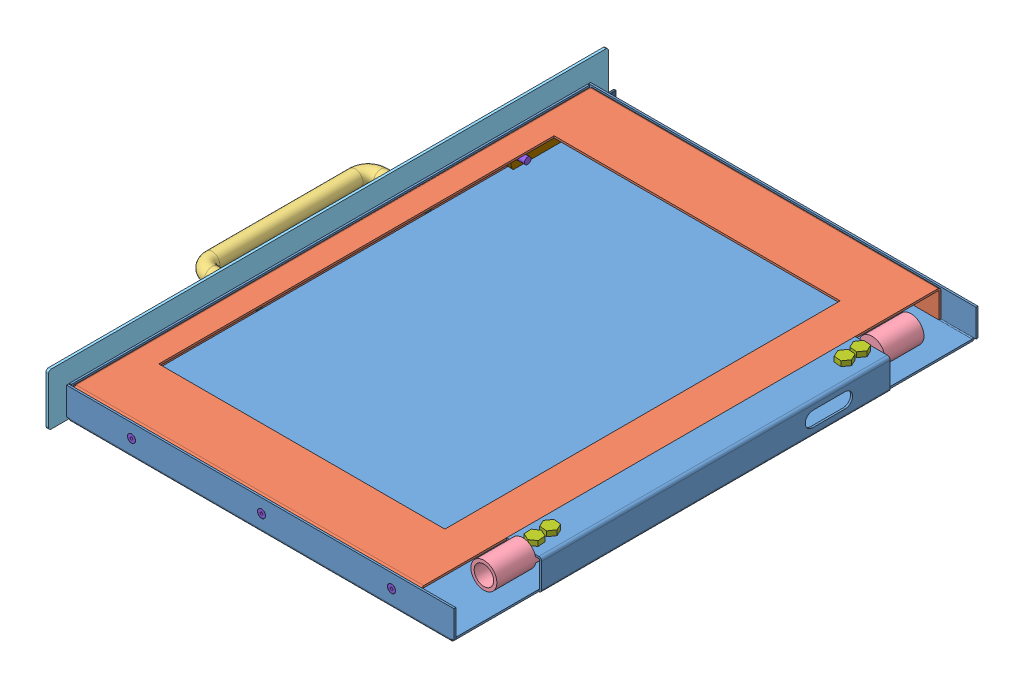
SolidWorks assembly MONITOR, configuration Valor predeterminado. Lengths in mm.
Overall size (341 40 430.56).
23 component instances, 10 part files, 51 mates.
Components (placement in the parent):
- 500040100-1: 500040100 [Valor predeterminado] at origin size (298 23.5 403.09)
- 500100100-1: 500100100 [Valor predeterminado] at (1.5 20.5 -401.59) x (1 0 0) z (0 0 -1) size (269.5 21.26 400.09)
- 500110100-1: 500110100 [Valor predeterminado] at (-2 12 -269.045) x (0 0 1) z (1 0 0) size (142 12 41)
- 500070100-1: 500070100 [Default<Como usinado>] at (283.75 18.5 -67.3) x (1 0 0) z (0 0 -1) size (20 20 60)
- 500070100-2: 500070100 [Default<Como usinado>] at (283.75 18.5 -335.79) size (20 20 60)
- 500120100-1: 500120100 [Valor predeterminado] at (-2 18.5 -201.545) x (0 0 -1) z (-1 0 0) size (430.56 40 2)
- PARAFUSO ALLEN CILÍNDRICO DIN 912-1: PARAFUSO ALLEN CILÍNDRICO DIN 912 [M6x20] at (9 12 -269.045) x (0 0.596353 -0.802722) z (-1 0 0) size (10 10 26)
- PARAFUSO ALLEN CILÍNDRICO DIN 912-2: PARAFUSO ALLEN CILÍNDRICO DIN 912 [M6x20] at (9 12 -139.045) x (0 0.596353 -0.802722) z (-1 0 0) size (10 10 26)
- PARAFUSO SEXTAVADO DIN 933-1: PARAFUSO SEXTAVADO DIN 933 [M6 x 10] at (283.75 24.2 -88.3) x (-0.996406 0 -0.084704) z (0 -1 0) size (11.55 10 14.4)
- PARAFUSO SEXTAVADO DIN 933-2: PARAFUSO SEXTAVADO DIN 933 [M6 x 10] at (283.75 23.7 -76.3) x (-0.819858 0 0.572567) z (0 -1 0) size (11.55 10 14.4)
- PARAFUSO SEXTAVADO DIN 933-3: PARAFUSO SEXTAVADO DIN 933 [M6 x 10] at (283.75 24.2 -314.79) x (-0.996406 0 -0.084704) z (0 -1 0) size (11.55 10 14.4)
- PARAFUSO SEXTAVADO DIN 933-4: PARAFUSO SEXTAVADO DIN 933 [M6 x 10] at (283.75 24.2 -326.79) x (-0.996406 0 -0.084704) z (0 -1 0) size (11.55 10 14.4)
- PARAFUSO ALLEN CÔNICO DIN 7991-4: PARAFUSO ALLEN CÔNICO DIN 7991 [M3x05] at (250 11.3683 -398.09) x (0 0 -1) z (-0.251703 0.967804 0) size (5 6 6)
- PARAFUSO ALLEN CÔNICO DIN 7991-5: PARAFUSO ALLEN CÔNICO DIN 7991 [M3x05] at (150 11.3683 -398.09) x (0 0 -1) z (-0.251703 0.967804 0) size (5 6 6)
- PARAFUSO ALLEN CÔNICO DIN 7991-6: PARAFUSO ALLEN CÔNICO DIN 7991 [M3x05] at (50 11.3683 -398.09) x (0 0 -1) z (-0.997322 0.073139 0) size (5 6 6)
- PARAFUSO ALLEN CÔNICO DIN 7991-9: PARAFUSO ALLEN CÔNICO DIN 7991 [M3x05] at (50 11.3683 -5) x (0 0 1) z (0.138211 -0.990403 0) size (5 6 6)
- PARAFUSO ALLEN CÔNICO DIN 7991-10: PARAFUSO ALLEN CÔNICO DIN 7991 [M3x05] at (150 11.3683 -5) x (0 0 1) z (-0.138211 0.990403 0) size (5 6 6)
- PARAFUSO ALLEN CÔNICO DIN 7991-11: PARAFUSO ALLEN CÔNICO DIN 7991 [M3x05] at (250 11.3683 -5) x (0 0 1) z (-0.697753 -0.716338 0) size (5 6 6)
- 500280100-1: 500280100 [Valor predeterminado] at (11.5 12 -345.09) x (0 0 -1) z (-1 0 0) size (70 13.8 8.84)
- 500290100-1: 500290100 [Valor predeterminado] at (9.5 16.5 -359.94) x (0 0 -1) z (-1 0 0) size (53.15 9 13.04)
- PARAFUSO ALLEN CÔNICO DIN 7991-12: PARAFUSO ALLEN CÔNICO DIN 7991 [M6x20] at (18 12 -336.79) x (-1 0 0) z (0 -0.942232 -0.334961) size (20 12 12)
- PARAFUSO ALLEN CÔNICO DIN 7991-13: PARAFUSO ALLEN CÔNICO DIN 7991 [M6x20] at (18 12 -380.79) x (-1 0 0) z (0 0.921959 -0.387289) size (20 12 12)
- PARAFUSO ALLEN CÔNICO DIN 7991-14: PARAFUSO ALLEN CÔNICO DIN 7991 [M6x20] at (18 12 -22.3) x (-1 0 0) z (0 0.834917 -0.550376) size (20 12 12)
Mates (geometry in assembly coordinates):
- Coincidente63: coincident anti-aligned: plane of 500040100-1 through (0 0 -1.5) normal (0 0 -1); plane of 500100100-1 through (1.5 20.5 -1.5) normal (0 0 1)
- Coincidente64: coincident aligned: plane of 500040100-1 through (0 22 -400.8534) normal (0 1 0); plane of 500100100-1 through (1.5 22 -401.59) normal (0 1 0)
- Coincidente65: coincident anti-aligned: plane of 500040100-1 through (1.5 0 0) normal (1 0 0); plane of 500100100-1 through (1.5 20.5 -401.59) normal (-1 0 0)
- Concêntrico15: concentric anti-aligned: cylinder of 500040100-1 through (0 12 -269.045) axis (-1 0 0) radius 3.3; cylinder of 500110100-1 through (-27 12 -269.045) axis (1 0 0) radius 6
- Concêntrico16: concentric anti-aligned: cylinder of 500040100-1 through (0 12 -139.045) axis (-1 0 0) radius 3.3; cylinder of 500110100-1 through (-27 12 -139.045) axis (1 0 0) radius 6
- Coincidente61: coincident anti-aligned: plane of 500040100-1 through (0 20.5 0) normal (0 -1 0); plane of 500070100-1 through (273.75 20.5 -67.3) normal (0 1 0)
- Largura5: width anti-aligned: plane of 500040100-1 through (296.5 0 0) normal (-1 0 0); plane of 500040100-1 through (271 22 -2.2366) normal (-1 0 0); cylinder of 500070100-1 through (283.75 18.5 -37.3) axis (0 0 -1) radius 10
- Paralelo15: parallel aligned: plane of 500040100-1 through (0 22 0) normal (0 1 0); plane of 500070100-2 through (273.75 20.5 -335.79) normal (0 1 0)
- Coincidente67: coincident anti-aligned: plane of 500040100-1 through (0 0 0) normal (-1 0 0); plane of 500120100-1 through (0 18.5 -201.545) normal (1 0 0)
- Paralelo17: parallel aligned: plane of 500040100-1 through (0 -1.5 0) normal (0 -1 0); plane of 500120100-1 through (0 -1.5 13.735) normal (0 -1 0)
- Largura6: width anti-aligned: plane of 500120100-1 through (0 -1.5 13.735) normal (0 0 1); plane of 500120100-1 through (0 -1.5 -416.825) normal (0 0 -1); plane of 500040100-1 through (0 0 -403.09) normal (0 0 -1); plane of 500040100-1 through (0 0 0) normal (0 0 1)
- Coincidente68: coincident aligned: plane of 500040100-1 through (0 -1.5 0) normal (0 -1 0); plane of 500120100-1 through (0 -1.5 13.735) normal (0 -1 0)
- Concêntrico18: concentric anti-aligned: cylinder of 500040100-1 through (283.75 22 -88.3) axis (0 1 0) radius 2.5; cylinder of 500070100-1 through (283.75 16.5 -88.3) axis (0 -1 0) radius 2.5
- Concêntrico19: concentric aligned: cylinder of 500040100-1 through (283.75 22 -326.79) axis (0 1 0) radius 2.5; cylinder of 500070100-2 through (283.75 20.5 -326.79) axis (0 1 0) radius 2.5
- Coincidente73: coincident anti-aligned: plane of 500110100-1 through (-2 12 -139.045) normal (1 0 0); plane of 500120100-1 through (-2 18.5 -201.545) normal (-1 0 0)
- Concêntrico29: concentric anti-aligned: cone of 500110100-1 through (-19 12 -269.045) axis (-1 0 0); cylinder of PARAFUSO ALLEN CILÍNDRICO DIN 912-1 through (-17 12 -269.045) axis (1 0 0) radius 2.5
- Coincidente87: coincident anti-aligned: plane of 500100100-1 through (3 20.5 -401.59) normal (1 0 0); plane of PARAFUSO ALLEN CILÍNDRICO DIN 912-1 through (3 12 -269.045) normal (-1 0 0)
- Concêntrico30: concentric aligned: cylinder of 500110100-1 through (-2 12 -139.045) axis (1 0 0) radius 2.5; cylinder of PARAFUSO ALLEN CILÍNDRICO DIN 912-2 through (-17 12 -139.045) axis (1 0 0) radius 2.5
- Tangente1: tangent: plane of 500100100-1 through (3 20.5 -401.59) normal (1 0 0); circle of PARAFUSO ALLEN CILÍNDRICO DIN 912-2
- Concêntrico31: concentric aligned: cylinder of 500040100-1 through (283.75 22 -88.3) axis (0 1 0) radius 2.5; cylinder of PARAFUSO SEXTAVADO DIN 933-1 through (283.75 12 -88.3) axis (0 1 0) radius 2.6
- Concêntrico32: concentric aligned: cylinder of 500040100-1 through (283.75 22 -76.3) axis (0 1 0) radius 2.5; cylinder of PARAFUSO SEXTAVADO DIN 933-2 through (283.75 11.5 -76.3) axis (0 1 0) radius 2.6
- Coincidente89: coincident anti-aligned: plane of 500040100-1 through (0 22 0) normal (0 1 0); plane of PARAFUSO SEXTAVADO DIN 933-2 through (273.787 22 -75.4407) normal (0 -1 0)
- Coincidente90: coincident anti-aligned: plane of 500040100-1 through (0 22 0) normal (0 1 0); plane of PARAFUSO SEXTAVADO DIN 933-1 through (274.6973 22 -84.0515) normal (0 -1 0)
- Concêntrico33: concentric aligned: cylinder of 500070100-2 through (283.75 20.5 -314.79) axis (0 1 0) radius 2.5; cylinder of PARAFUSO SEXTAVADO DIN 933-3 through (283.75 12 -314.79) axis (0 1 0) radius 2.6
- Coincidente91: coincident anti-aligned: plane of 500040100-1 through (0 22 0) normal (0 1 0); plane of PARAFUSO SEXTAVADO DIN 933-3 through (274.6973 22 -310.5415) normal (0 -1 0)
- Concêntrico34: concentric aligned: cylinder of 500070100-2 through (283.75 20.5 -326.79) axis (0 1 0) radius 2.5; cylinder of PARAFUSO SEXTAVADO DIN 933-4 through (283.75 12 -326.79) axis (0 1 0) radius 2.6
- Coincidente92: coincident anti-aligned: plane of 500040100-1 through (0 22 0) normal (0 1 0); plane of PARAFUSO SEXTAVADO DIN 933-4 through (274.6973 22 -322.5415) normal (0 -1 0)
- Concêntrico36: concentric anti-aligned: cylinder of 500100100-1 through (250 11.3683 -401.59) axis (0 0 -1) radius 1.25; cylinder of PARAFUSO ALLEN CÔNICO DIN 7991-4 through (250 11.3683 -387.9867) axis (0 0 1) radius 1.25
- Coincidente93: coincident aligned: plane of 500040100-1 through (0 0 -403.09) normal (0 0 -1); plane of PARAFUSO ALLEN CÔNICO DIN 7991-4 through (247.0966 10.6132 -403.09) normal (0 0 -1)
- Concêntrico37: concentric anti-aligned: cylinder of 500100100-1 through (150 11.3683 -401.59) axis (0 0 -1) radius 1.25; cylinder of PARAFUSO ALLEN CÔNICO DIN 7991-5 through (150 11.3683 -387.9867) axis (0 0 1) radius 1.25
- Coincidente94: coincident aligned: plane of 500040100-1 through (0 0 -403.09) normal (0 0 -1); plane of PARAFUSO ALLEN CÔNICO DIN 7991-5 through (147.0966 10.6132 -403.09) normal (0 0 -1)
- Concêntrico38: concentric anti-aligned: cylinder of 500100100-1 through (50 11.3683 -401.59) axis (0 0 -1) radius 1.25; cylinder of PARAFUSO ALLEN CÔNICO DIN 7991-6 through (50 11.3683 -387.9867) axis (0 0 1) radius 1.25
- Coincidente95: coincident aligned: plane of 500040100-1 through (0 0 -403.09) normal (0 0 -1); plane of PARAFUSO ALLEN CÔNICO DIN 7991-6 through (49.7806 8.3763 -403.09) normal (0 0 -1)
- Concêntrico41: concentric aligned: cone of 500040100-1 through (50 11.3683 0) axis (0 0 -1); cylinder of PARAFUSO ALLEN CÔNICO DIN 7991-9 through (50 11.3683 -15.1033) axis (0 0 -1) radius 1.25
- Coincidente98: coincident aligned: plane of 500040100-1 through (0 0 0) normal (0 0 1); plane of PARAFUSO ALLEN CÔNICO DIN 7991-9 through (47.0288 10.9537 0) normal (0 0 1)
- Concêntrico42: concentric anti-aligned: cylinder of 500100100-1 through (150 11.3683 -1.5) axis (0 0 1) radius 1.25; cylinder of PARAFUSO ALLEN CÔNICO DIN 7991-10 through (150 11.3683 -15.1033) axis (0 0 -1) radius 1.25
- Coincidente99: coincident aligned: plane of 500040100-1 through (0 0 0) normal (0 0 1); plane of PARAFUSO ALLEN CÔNICO DIN 7991-10 through (152.9712 11.7829 0) normal (0 0 1)
- Concêntrico43: concentric anti-aligned: cylinder of 500100100-1 through (250 11.3683 -1.5) axis (0 0 1) radius 1.25; cylinder of PARAFUSO ALLEN CÔNICO DIN 7991-11 through (250 11.3683 -15.1033) axis (0 0 -1) radius 1.25
- Coincidente100: coincident aligned: plane of 500040100-1 through (0 0 0) normal (0 0 1); plane of PARAFUSO ALLEN CÔNICO DIN 7991-11 through (247.851 13.4616 0) normal (0 0 1)
- Coincidente101: coincident anti-aligned: plane of 500280100-1 through (8 7.5 -343.7724) normal (0 1 0); plane of 500290100-1 through (8 7.5 -359.94) normal (0 -1 0)
- Coincidente102: coincident anti-aligned: plane of 500280100-1 through (8 7.5 -343.7724) normal (1 0 0); plane of 500290100-1 through (8 16.5 -359.94) normal (-1 0 0)
- DistânciaLimite1: limit distance = 13 mm aligned: plane of 500280100-1 through (3 5.1 -400.09) normal (0 0 -1); plane of 500290100-1 through (8 16.5 -413.09) normal (0 0 -1)
- Coincidente105: coincident anti-aligned: plane of 500100100-1 through (1.5 20.5 -400.09) normal (0 0 1); plane of 500280100-1 through (3 5.1 -400.09) normal (0 0 -1)
- Largura7: width anti-aligned: plane of 500280100-1 through (3 18.9 -331.7712) normal (0 1 0); plane of 500280100-1 through (3 5.1 -331.7712) normal (0 -1 0); cylinder of 500110100-1 through (-37 12 -259.045) axis (0 0 1) radius 6
- Concêntrico44: concentric anti-aligned: cylinder of 500040100-1 through (0 12 -336.79) axis (-1 0 0) radius 2.5; cylinder of PARAFUSO ALLEN CÔNICO DIN 7991-12 through (28.1033 12 -336.79) axis (1 0 0) radius 2.5
- Coincidente106: coincident aligned: plane of 500120100-1 through (-2 18.5 -201.545) normal (-1 0 0); plane of PARAFUSO ALLEN CÔNICO DIN 7991-12 through (-2 14.0098 -342.4434) normal (-1 0 0)
- Concêntrico451: concentric anti-aligned: cylinder of 500100100-1 through (1.5 12 -380.79) axis (-1 0 0) radius 2.5; cylinder of PARAFUSO ALLEN CÔNICO DIN 7991-13 through (28.1033 12 -380.79) axis (1 0 0) radius 2.5
- Coincidente1071: coincident aligned: plane of 500120100-1 through (-2 18.5 -201.545) normal (-1 0 0); plane of PARAFUSO ALLEN CÔNICO DIN 7991-13 through (-2 14.3237 -375.2582) normal (-1 0 0)
- Coincidente1091: coincident anti-aligned: plane of 500100100-1 through (3 20.5 -401.59) normal (1 0 0); plane of 500280100-1 through (3 12 -345.09) normal (-1 0 0)
- Concêntrico461: concentric anti-aligned: cylinder of 500040100-1 through (0 12 -22.3) axis (-1 0 0) radius 2.5; cylinder of PARAFUSO ALLEN CÔNICO DIN 7991-14 through (28.1033 12 -22.3) axis (1 0 0) radius 2.5
- Coincidente1101: coincident aligned: plane of 500120100-1 through (-2 18.5 -201.545) normal (-1 0 0); plane of PARAFUSO ALLEN CÔNICO DIN 7991-14 through (-2 15.3023 -17.2905) normal (-1 0 0)
